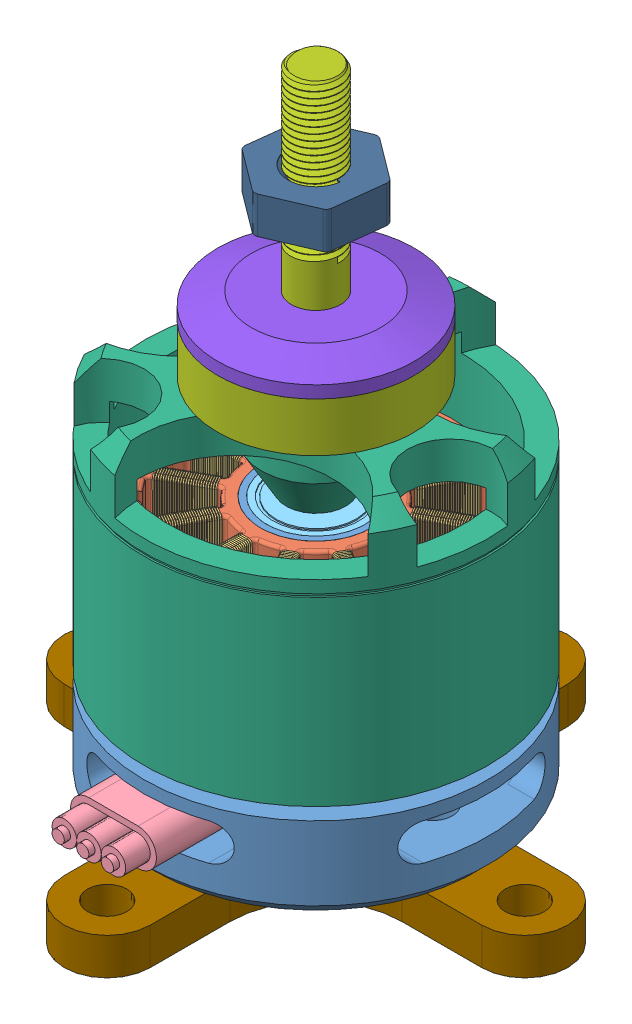
SolidWorks assembly SunnySky X2212_13_980kV, configuration Default. Lengths in mm.
Overall size (41 53.8 41).
22 component instances, 10 part files, 28 mates.
Components (placement in the parent):
- Housing_Bottom-1: Housing_Bottom [Default] at origin size (28 20 28)
- Stator-1: Stator [Default] at (0 8 0) size (22 12.2 22)
  - Stator_Steelcore-1: Stator_Steelcore [Default] at origin size (22 12.05 22)
  - Stator_Coil-1: Stator_Coil [Default] at (-2.8504 6 4.9371) x (0.5 0 -0.866025) z (0.866025 0 0.5) size (4.11 12.2 1.21)
  - Stator_Coil-2: Stator_Coil [Default] at (0 6 5.7009) x (0 0 -1) z (1 0 0) size (4.11 12.2 1.21)
  - Stator_Coil-3: Stator_Coil [Default] at (2.8504 6 4.9371) x (-0.5 0 -0.866025) z (0.866025 0 -0.5) size (4.11 12.2 1.21)
  - Stator_Coil-4: Stator_Coil [Default] at (4.9371 6 2.8504) x (-0.866025 0 -0.5) z (0.5 0 -0.866025) size (4.11 12.2 1.21)
  - Stator_Coil-5: Stator_Coil [Default] at (5.7009 6 0) x (-1 0 0) z (0 0 -1) size (4.11 12.2 1.21)
  - Stator_Coil-6: Stator_Coil [Default] at (4.9371 6 -2.8504) x (-0.866025 0 0.5) z (-0.5 0 -0.866025) size (4.11 12.2 1.21)
  - Stator_Coil-7: Stator_Coil [Default] at (2.8504 6 -4.9371) x (-0.5 0 0.866025) z (-0.866025 0 -0.5) size (4.11 12.2 1.21)
  - Stator_Coil-8: Stator_Coil [Default] at (0 6 -5.7009) x (0 0 1) z (-1 0 0) size (4.11 12.2 1.21)
  - Stator_Coil-9: Stator_Coil [Default] at (-2.8504 6 -4.9371) x (0.5 0 0.866025) z (-0.866025 0 0.5) size (4.11 12.2 1.21)
  - Stator_Coil-10: Stator_Coil [Default] at (-4.9371 6 -2.8504) x (0.866025 0 0.5) z (-0.5 0 0.866025) size (4.11 12.2 1.21)
  - Stator_Coil-11: Stator_Coil [Default] at (-5.7009 6 0) size (4.11 12.2 1.21)
  - Stator_Coil-12: Stator_Coil [Default] at (-4.9371 6 2.8504) x (0.866025 0 -0.5) z (0.5 0 0.866025) size (4.11 12.2 1.21)
- Wiring-1: Wiring [Default] at (0.0116 4.5 16.5) x (1 0 0) z (0 0 -1) size (7 3 14.5)
- Rotor-1: Rotor [Default] x (-0.598049 0 0.80146) z (-0.80146 0 -0.598049) size (8 31.7 8)
- Housing_Upper-1: Housing_Upper [Default] at (0 8 0) x (-0.598049 0 0.80146) z (-0.80146 0 -0.598049) size (28 22 28)
- CapScrew-1: CapScrew [Default] at (0 28.5 0) x (0.117196 0 -0.993109) z (0.993109 0 0.117196) size (16 22.3 16)
- Cap-1: Cap [Default] at (0 32.5 0) x (0.117196 0 -0.993109) z (0.993109 0 0.117196) size (16 2 16)
- CrossBase-1: CrossBase [Default] at (0 -3 0) size (41 3 41)
- Nut-1: Nut [Default] at (0 40.4 0) x (0.117196 0 -0.993109) z (0.993109 0 0.117196) size (9.08 3.45 8)
Mates (geometry in assembly coordinates):
- Concentric1: concentric aligned: cylinder of Stator-1/Stator_Steelcore-1 through (0 20 0) axis (0 -1 0) radius 4.5; cylinder of Housing_Bottom-1 through (0 20 0) axis (0 -1 0) radius 4.5
- Coincident1: coincident aligned: plane of Housing_Bottom-1 through (0 20 0) normal (0 1 0); plane of Stator-1/Stator_Steelcore-1 through (0 20 0) normal (0 1 0)
- Coincident2: coincident anti-aligned: plane of Housing_Bottom-1 through (0 3 0) normal (0 1 0); plane of Wiring-1 through (-1.9884 3 6.5) normal (0 -1 0)
- Lock1: lock: unknown of Housing_Bottom-1; unknown of Wiring-1
- Tangent1: tangent anti-aligned: cylinder of Housing_Bottom-1 through (0 20 0) axis (0 -1 0) radius 4.5; plane of Wiring-1 through (0.0116 4.5 4.5) normal (0 0 -1)
- Coincident6: coincident aligned: plane of Housing_Bottom-1 through (0 20 0) normal (0 1 0); plane of Rotor-1 through (0 20 0) normal (0 1 0)
- Concentric2: concentric aligned: cylinder of Housing_Bottom-1 through (0 14.3137 0) axis (0 -1 0) radius 4; cylinder of Rotor-1 through (0 20 0) axis (0 -1 0) radius 4
- Concentric3: concentric anti-aligned: cylinder of Rotor-1 through (0 30 0) axis (0 -1 0) radius 1.5; cylinder of Housing_Upper-1 through (0 8 0) axis (0 1 0) radius 1.5
- Distance1: distance = 8 mm aligned: plane of Housing_Upper-1; plane of Housing_Bottom-1 through (0 0 0) normal (0 1 0)
- Coincident10: coincident aligned: plane of Housing_Bottom-1 through (0 0 0) normal (0 0 1); plane of Stator-1/Stator_Steelcore-1 through (0 8 0) normal (0 0 1)
- Coincident11: coincident aligned: plane of Rotor-1 through (0 0 0) normal (-0.80146 0 -0.598049); plane of Housing_Upper-1 through (0 8 0) normal (-0.80146 0 -0.598049)
- Coincident12: coincident aligned: plane of Housing_Bottom-1 through (0 0 0) normal (0 0 1); plane of assembly through (0 0 0) normal (0 0 1)
- Coincident13: coincident aligned: plane of Housing_Bottom-1 through (0 0 0) normal (0 1 0); plane of assembly through (0 0 0) normal (0 1 0)
- Coincident14: coincident aligned: plane of Housing_Bottom-1 through (0 0 0) normal (1 0 0); plane of assembly through (0 0 0) normal (1 0 0)
- Concentric4: concentric anti-aligned: cylinder of Housing_Upper-1 through (0 9.9135 0) axis (0 1 0) radius 4.45; cylinder of CapScrew-1 through (0 30 0) axis (0 -1 0) radius 4.5
- Concentric5: concentric aligned: cylinder of Housing_Upper-1 through (-2.3704 28.5 -5.5119) axis (0 1 0) radius 0.625; cylinder of CapScrew-1 through (-2.3704 32.5 -5.5119) axis (0 1 0) radius 0.85
- Concentric6: concentric aligned: cylinder of Housing_Upper-1 through (5.9587 28.5 0.7032) axis (0 1 0) radius 0.625; cylinder of CapScrew-1 through (5.9587 32.5 0.7032) axis (0 1 0) radius 0.85
- Concentric7: concentric aligned: cylinder of Housing_Upper-1 through (-3.5883 28.5 4.8088) axis (0 1 0) radius 0.625; cylinder of CapScrew-1 through (-3.5883 32.5 4.8088) axis (0 1 0) radius 0.85
- Coincident15: coincident anti-aligned: plane of Housing_Upper-1 through (0 28.5 0) normal (0 1 0); plane of CapScrew-1 through (0 28.5 0) normal (0 -1 0)
- Concentric8: concentric anti-aligned: cylinder of CapScrew-1 through (0 50.5 0) axis (0 -1 0) radius 2; cylinder of Cap-1 through (0 32.5 0) axis (0 1 0) radius 2
- Coincident16: coincident anti-aligned: plane of CapScrew-1 through (0 32.5 0) normal (0 1 0); plane of Cap-1 through (0 32.5 0) normal (0 -1 0)
- Concentric19: concentric aligned: cylinder of Housing_Bottom-1 through (0 0 8) axis (0 -1 0) radius 1.6; cylinder of CrossBase-1 through (0 -3 8) axis (0 -1 0) radius 1.6
- Concentric21: concentric aligned: cylinder of Housing_Bottom-1 through (0 0 -8) axis (0 -1 0) radius 1.6; cylinder of CrossBase-1 through (0 -3 -8) axis (0 -1 0) radius 1.6
- Coincident18: coincident anti-aligned: plane of Housing_Bottom-1 through (0 0 0) normal (0 -1 0); plane of CrossBase-1 through (0 0 0) normal (0 1 0)
- Coincident19: coincident aligned: plane of CapScrew-1 through (0 28.5 0) normal (0.993109 0 0.117196); plane of Cap-1 through (0 32.5 0) normal (0.993109 0 0.117196)
- Concentric22: concentric anti-aligned: cylinder of CapScrew-1 through (0 50.5 0) axis (0 -1 0) radius 2; cylinder of Nut-1 through (0 40.4 0) axis (0 1 0) radius 2.25
- Parallel3: parallel aligned: plane of Cap-1 through (0 34.5 0) normal (0 1 0); plane of Nut-1 through (0 43.4 0) normal (0 1 0)
- Coincident26: coincident aligned: plane of Cap-1 through (0 32.5 0) normal (0.993109 0 0.117196); plane of Nut-1 through (0 40.4 0) normal (0.993109 0 0.117196)
